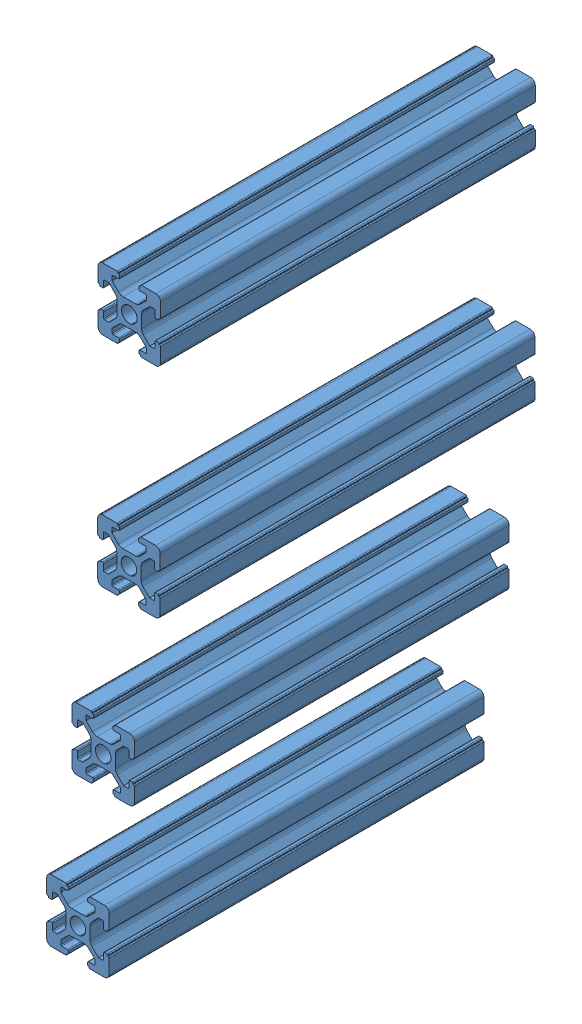
SolidWorks assembly CNC, configuration Default. Lengths in mm.
Overall size (151.8 251 384.72).
4 component instances, 1 part files, 0 mates.
Components (placement in the parent):
- 2020-1: 2020 [Default] at (229.1722 84.7778 -158.9242) size (40 40 240)
- 2020-2: 2020 [Default] at (197.5077 140.3698 -206.7416) size (40 40 240)
- 2020-3: 2020 [Default] at (163.4424 202.28 -257.3288) size (40 40 240)
- 2020-4: 2020 [Default] at (117.3736 295.7792 -303.6428) size (40 40 240)
